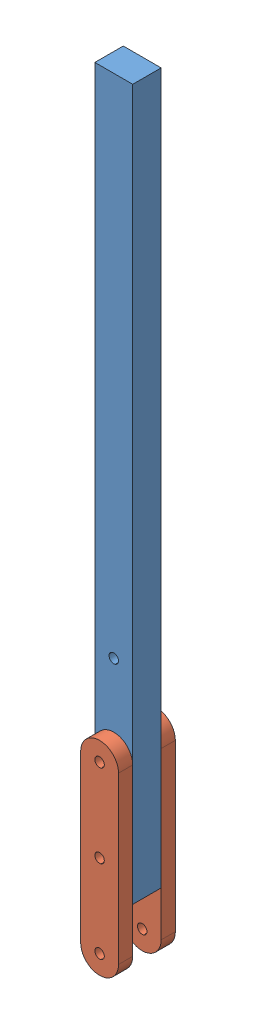
SolidWorks assembly spoke, configuration Default. Lengths in mm.
Overall size (8 163.5 12).
3 component instances, 2 part files, 6 mates.
Components (placement in the parent):
- long_spoke-1: long_spoke [Default] at (-11.8607 -1.6601 119.1869) size (8 150 6)
- sopke_part-1: sopke_part [Default] at (75.7546 -14.8367 119.1869) x (-1 0 0) z (0 0 -1) size (8 43 3)
- sopke_part-2: sopke_part [Default] at (75.7546 -14.8367 128.1869) x (-1 0 0) z (0 0 -1) size (8 43 3)
Mates (geometry in assembly coordinates):
- Coincident1: coincident anti-aligned: plane of long_spoke-1 through (-11.8607 -1.6601 125.1869) normal (0 0 1); plane of sopke_part-2 through (39.961 30.8532 125.1869) normal (0 0 -1)
- Concentric1: concentric anti-aligned: cylinder of long_spoke-1 through (39.961 30.8532 125.1869) axis (0 0 -1) radius 1; cylinder of sopke_part-2 through (39.961 30.8532 125.1869) axis (0 0 1) radius 1
- Concentric2: concentric anti-aligned: cylinder of long_spoke-1 through (39.961 13.3532 125.1869) axis (0 0 -1) radius 1; cylinder of sopke_part-2 through (39.961 13.3532 125.1869) axis (0 0 1) radius 1
- Coincident2: coincident: plane of long_spoke-1 through (-11.8607 -1.6601 119.1869) normal (0 0 -1); plane of sopke_part-1 through (39.961 30.8532 119.1869) normal (0 0 1)
- Concentric5: concentric: cylinder of long_spoke-1 through (39.961 30.8532 125.1869) axis (0 0 -1) radius 1; cylinder of sopke_part-1 through (39.961 30.8532 116.1869) axis (0 0 1) radius 1
- Concentric6: concentric anti-aligned: cylinder of long_spoke-1 through (39.961 13.3532 125.1869) axis (0 0 -1) radius 1; cylinder of sopke_part-1 through (39.961 13.3532 116.1869) axis (0 0 1) radius 1
